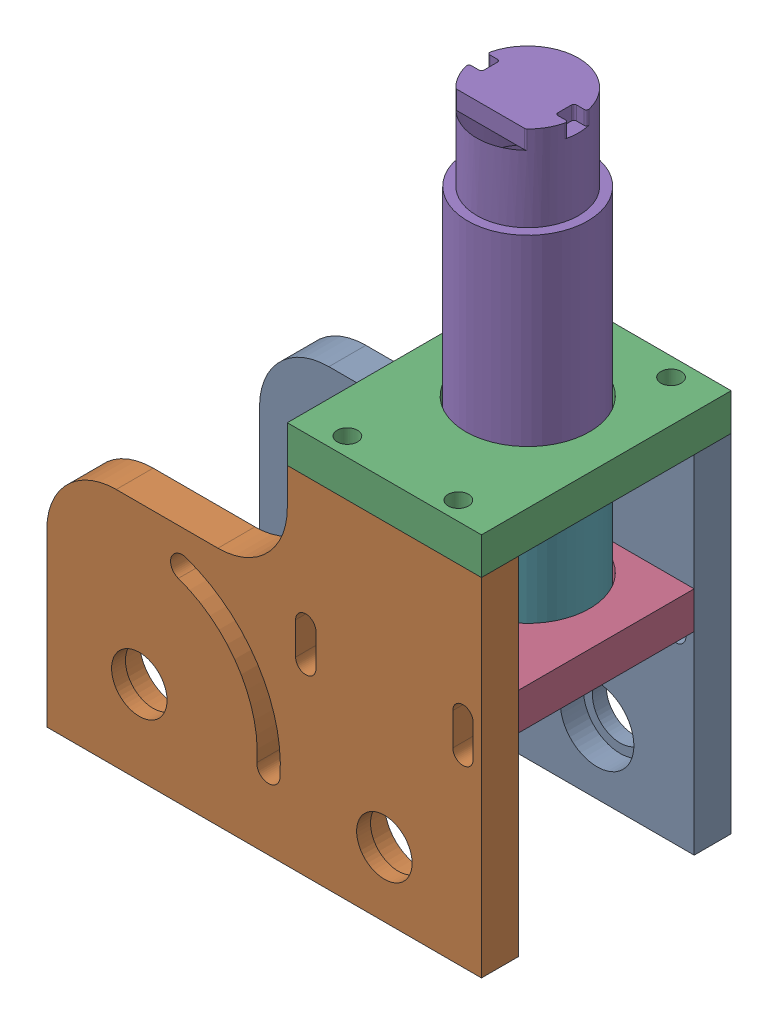
SolidWorks assembly Assemblage_Bloc_Moteur_Droit_Alege, configuration Défaut. Lengths in mm.
Overall size (94 140.79 54).
5 component instances, 5 part files, 12 mates.
Components (placement in the parent):
- Plaque_Droite_Bloc_Moteur_Droit-1: Plaque_Droite_Bloc_Moteur_Droit [Défaut] at (-143.6129 -21.156 91.0404) size (94 75 8)
- Plaque_Gauche_Bloc_Moteur_Droit-1: Plaque_Gauche_Bloc_Moteur_Droit [Défaut] at (-143.6129 -21.156 137.0404) size (94 75 8)
- Plaque_Axe_Moteur-1: Plaque_Axe_Moteur [Défaut] at (-91.6129 53.844 137.0404) size (42 8 54)
- Plaque_Support_Moteur-1: Plaque_Support_Moteur [Défaut] at (-91.6129 20.7343 129.0404) size (42 8 38)
- Moteur_Faulhaber_D26-1: Moteur_Faulhaber_D26 [Défaut] at (-70.6129 59.1343 106.0404) x (-1 0 0) z (0 -1 0) size (26 26 113.9)
Mates (geometry in assembly coordinates):
- Coïncidente1: coincident aligned: plane of Plaque_Droite_Bloc_Moteur_Droit-1 through (-143.6129 -21.156 83.0404) normal (0 -1 0); plane of Plaque_Gauche_Bloc_Moteur_Droit-1 through (-143.6129 -21.156 129.0404) normal (0 -1 0)
- Coaxiale4: concentric aligned: cylinder of Plaque_Droite_Bloc_Moteur_Droit-1 through (-58.6129 23.844 87.0404) axis (0 1 0) radius 1.5; cylinder of Plaque_Axe_Moteur-1 through (-58.6129 53.844 87.0404) axis (0 1 0) radius 2.2
- Coaxiale5: concentric aligned: cylinder of Plaque_Droite_Bloc_Moteur_Droit-1 through (-82.6129 23.844 87.0404) axis (0 1 0) radius 1.5; cylinder of Plaque_Axe_Moteur-1 through (-82.6129 53.844 87.0404) axis (0 1 0) radius 2.2
- Coïncidente3: coincident anti-aligned: plane of Plaque_Droite_Bloc_Moteur_Droit-1 through (-91.6129 53.844 83.0404) normal (0 1 0); plane of Plaque_Axe_Moteur-1 through (-91.6129 53.844 137.0404) normal (0 -1 0)
- Coaxiale7: concentric aligned: cylinder of Plaque_Gauche_Bloc_Moteur_Droit-1 through (-58.6129 23.844 133.0404) axis (0 1 0) radius 1.5; cylinder of Plaque_Axe_Moteur-1 through (-58.6129 53.844 133.0404) axis (0 1 0) radius 2.2
- Coaxiale21: concentric anti-aligned: cylinder of Plaque_Support_Moteur-1 through (-70.6129 20.7343 96.0404) axis (0 1 0) radius 1.8; cylinder of Moteur_Faulhaber_D26-1 through (-70.6129 26.7343 96.0404) axis (0 -1 0) radius 1.8
- Coaxiale22: concentric anti-aligned: cylinder of Plaque_Support_Moteur-1 through (-70.6129 20.7343 116.0404) axis (0 1 0) radius 1.8; cylinder of Moteur_Faulhaber_D26-1 through (-70.6129 26.7343 116.0404) axis (0 -1 0) radius 1.8
- Coïncidente14: coincident anti-aligned: plane of Plaque_Support_Moteur-1 through (-70.6129 22.7343 106.0404) normal (0 1 0); plane of Moteur_Faulhaber_D26-1 through (-70.6129 22.7343 106.0404) normal (0 -1 0)
- Coïncidente16: coincident anti-aligned: plane of Plaque_Droite_Bloc_Moteur_Droit-1 through (-143.6129 -21.156 91.0404) normal (0 0 1); plane of Plaque_Support_Moteur-1 through (-91.6129 20.7333 91.0404) normal (0 0 -1)
- Coaxiale26: concentric aligned: cylinder of Plaque_Gauche_Bloc_Moteur_Droit-1 through (-82.6129 23.844 133.0404) axis (0 1 0) radius 1.5; cylinder of Plaque_Axe_Moteur-1 through (-82.6129 53.844 133.0404) axis (0 1 0) radius 2.2
- Rainure3: slot aligned: cylinder of Plaque_Gauche_Bloc_Moteur_Droit-1 through (-87.6129 18.844 137.0404) axis (0 0 -1) radius 2.2; cylinder of Plaque_Support_Moteur-1 through (-87.6129 24.7343 129.0404) axis (0 0 -1) radius 1.5; cylinder of Plaque_Gauche_Bloc_Moteur_Droit-1 through (-87.6129 25.844 137.0404) axis (0 0 -1) radius 2.2
- Rainure4: slot aligned: cylinder of Plaque_Gauche_Bloc_Moteur_Droit-1 through (-53.6129 18.844 137.0404) axis (0 0 -1) radius 2.2; cylinder of Plaque_Support_Moteur-1 through (-53.6129 24.7343 129.0404) axis (0 0 -1) radius 1.5; cylinder of Plaque_Gauche_Bloc_Moteur_Droit-1 through (-53.6129 25.844 137.0404) axis (0 0 -1) radius 2.2
